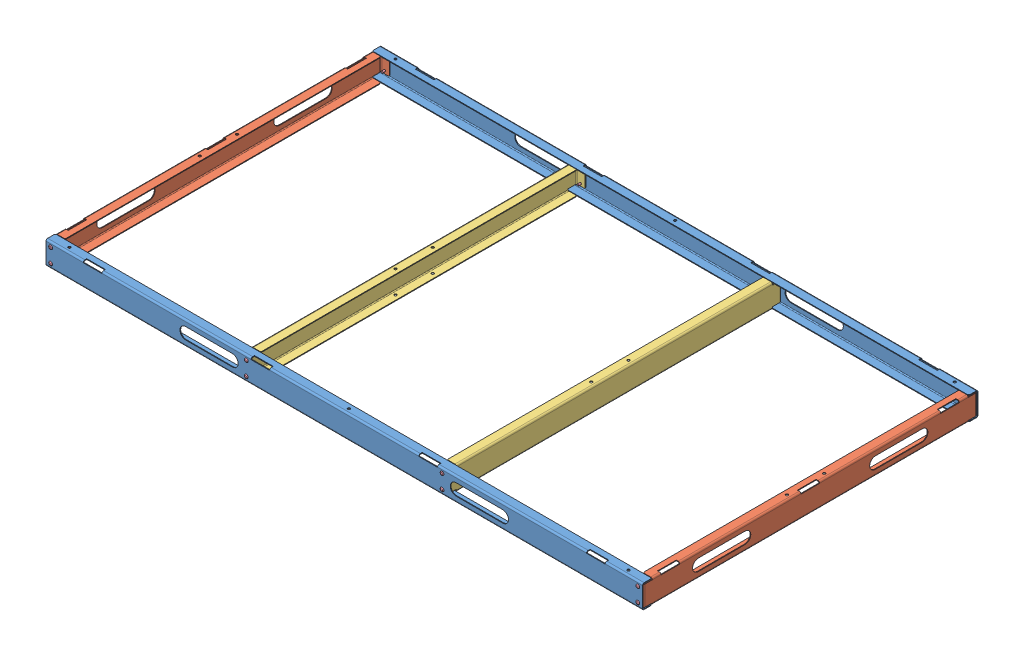
SolidWorks assembly GE-19063, configuration Default. Lengths in mm.
Overall size (1625.6 63.5 917.59).
22 component instances, 4 part files, 46 mates.
Components (placement in the parent):
- GE-19066-2: GE-19066 [Default] at (812.8 0 -457.2) x (0 0 -1) z (1 0 0) size (25.4 63.5 1625.6)
- GE-19064-2: GE-19064 [Default] at (-812.8 0 -430.5376) x (-1 0 0) z (0 0 -1) size (25.4 63.5 910.59)
- GE-19064-3: GE-19064 [Default] at (812.8 0 430.5224) size (25.4 63.5 910.59)
- GE-19066-3: GE-19066 [Default] at (-812.8 0 457.1848) x (0 0 1) z (-1 0 0) size (25.4 63.5 1625.6)
- GE-19065-1: GE-19065 [Default] at (279.4 0 -0.0076) size (25.4 63.5 910.59)
- GE-19065-2: GE-19065 [Default] at (-279.4 63.5 -0.0076) x (-1 0 0) z (0 0 1) size (25.4 63.5 910.59)
- rivet_.1875_.126-.25-2: rivet_.1875_.126-.25 [Default] at (-800.1 50.8 457.1848) size (10.01 10.01 13.03)
- rivet_.1875_.126-.25-10: rivet_.1875_.126-.25 [Default] at (-266.7 50.8 457.1848) x (0.959125 0.282984 0) z (0 0 1) size (10.01 10.01 13.03)
- rivet_.1875_.126-.25-11: rivet_.1875_.126-.25 [Default] at (-266.7 12.7 457.1848) x (0.928571 0.371154 0) z (0 0 1) size (10.01 10.01 13.03)
- rivet_.1875_.126-.25-12: rivet_.1875_.126-.25 [Default] at (266.7 50.8 457.1848) x (0.906989 0.421154 0) z (0 0 1) size (10.01 10.01 13.03)
- rivet_.1875_.126-.25-13: rivet_.1875_.126-.25 [Default] at (266.7 12.7 457.1848) x (0.902849 0.429957 0) z (0 0 1) size (10.01 10.01 13.03)
- rivet_.1875_.126-.25-14: rivet_.1875_.126-.25 [Default] at (800.1 50.8 457.1848) x (0.919615 0.39282 0) z (0 0 1) size (10.01 10.01 13.03)
- rivet_.1875_.126-.25-15: rivet_.1875_.126-.25 [Default] at (800.1 12.7 457.1848) x (0.952324 0.305088 0) z (0 0 1) size (10.01 10.01 13.03)
- rivet_.1875_.126-.25-18: rivet_.1875_.126-.25 [Default] at (-800.1 12.7 457.1848) x (0.987351 0.158553 0) z (0 0 1) size (10.01 10.01 13.03)
- rivet_.1875_.126-.25-20: rivet_.1875_.126-.25 [Default] at (800.1 50.8 -457.2) x (1 0 0) z (0 0 -1) size (10.01 10.01 13.03)
- rivet_.1875_.126-.25-21: rivet_.1875_.126-.25 [Default] at (800.1 12.7 -457.2) x (0.987351 0.158553 0) z (0 0 -1) size (10.01 10.01 13.03)
- rivet_.1875_.126-.25-22: rivet_.1875_.126-.25 [Default] at (266.7 50.8 -457.2) x (0.959125 0.282984 0) z (0 0 -1) size (10.01 10.01 13.03)
- rivet_.1875_.126-.25-23: rivet_.1875_.126-.25 [Default] at (266.7 12.7 -457.2) x (0.928571 0.371154 0) z (0 0 -1) size (10.01 10.01 13.03)
- rivet_.1875_.126-.25-24: rivet_.1875_.126-.25 [Default] at (-266.7 50.8 -457.2) x (0.906989 0.421154 0) z (0 0 -1) size (10.01 10.01 13.03)
- rivet_.1875_.126-.25-25: rivet_.1875_.126-.25 [Default] at (-266.7 12.7 -457.2) x (0.902849 0.429957 0) z (0 0 -1) size (10.01 10.01 13.03)
- rivet_.1875_.126-.25-26: rivet_.1875_.126-.25 [Default] at (-800.1 50.8 -457.2) x (0.919615 0.39282 0) z (0 0 -1) size (10.01 10.01 13.03)
- rivet_.1875_.126-.25-27: rivet_.1875_.126-.25 [Default] at (-800.1 12.7 -457.2) x (0.952324 0.305088 0) z (0 0 -1) size (10.01 10.01 13.03)
Mates (geometry in assembly coordinates):
- Distance5: distance = 457.2 mm: plane of GE-19066-2 through (812.8 0 -457.2) normal (0 0 -1); plane of assembly through (0 0 0) normal (0 0 1)
- Coincident19: coincident: plane of GE-19066-2 through (0 0 -457.2) normal (1 0 0); plane of assembly through (0 0 0) normal (1 0 0)
- Coincident20: coincident: plane of GE-19066-2 through (812.8 0 -457.2) normal (0 -1 0); plane of assembly through (0 0 0) normal (0 1 0)
- Concentric1: concentric: cylinder of GE-19066-2 through (-800.1 50.8 -431.8) axis (0 0 -1) radius 2.4638; cylinder of GE-19064-2 through (-800.1 50.8 455.2874) axis (0 0 -1) radius 2.4638
- Coincident21: coincident: plane of GE-19066-2 through (812.8 0 -455.3026) normal (0 0 1); plane of GE-19064-2 through (-812.8 0 -455.3026) normal (0 0 -1)
- Concentric4: concentric: cylinder of GE-19066-2 through (800.1 50.8 -431.8) axis (0 0 -1) radius 2.4638; cylinder of GE-19064-3 through (800.1 50.8 -455.3026) axis (0 0 1) radius 2.4638
- Coincident24: coincident: plane of GE-19066-2 through (812.8 0 -455.3026) normal (0 0 1); plane of GE-19064-3 through (812.8 0 -455.3026) normal (0 0 -1)
- Concentric5: concentric: cylinder of assembly; cylinder of assembly; cylinder of GE-19064-2 through (-800.1 50.8 455.2874) axis (0 0 -1) radius 2.4638; cylinder of GE-19066-3 through (-800.1 50.8 431.7848) axis (0 0 1) radius 2.4638
- Coincident25: coincident: plane of assembly; plane of assembly; plane of GE-19064-2 through (-812.8 0 455.2874) normal (0 0 1); plane of GE-19066-3 through (-812.8 0 455.2874) normal (0 0 -1)
- Concentric6: concentric: cylinder of assembly; cylinder of assembly; cylinder of GE-19066-3 through (266.7 50.8 431.7848) axis (0 0 1) radius 2.4638; cylinder of GE-19065-1 through (266.7 50.8 -455.3026) axis (0 0 1) radius 2.4638
- Coincident26: coincident: plane of assembly; plane of assembly; plane of GE-19066-3 through (-812.8 0 455.2874) normal (0 0 -1); plane of GE-19065-1 through (279.4 0 455.2874) normal (0 0 1)
- Concentric8: concentric: cylinder of assembly; cylinder of assembly; cylinder of GE-19066-3 through (-266.7 12.7 431.7848) axis (0 0 1) radius 2.4638; cylinder of GE-19065-2 through (-266.7 12.7 -455.3026) axis (0 0 1) radius 2.4638
- Concentric9: concentric: cylinder of assembly; cylinder of assembly; cylinder of GE-19066-3 through (-266.7 50.8 431.7848) axis (0 0 1) radius 2.4638; cylinder of GE-19065-2 through (-266.7 50.8 -455.3026) axis (0 0 1) radius 2.4638
- Coincident28: coincident: plane of assembly; plane of assembly; plane of GE-19066-3 through (-812.8 0 455.2874) normal (0 0 -1); plane of GE-19065-2 through (-279.4 63.5 455.2874) normal (0 0 1)
- Concentric10: concentric: cylinder of assembly; cylinder of assembly; cylinder of GE-19066-3 through (-800.1 50.8 431.7848) axis (0 0 1) radius 2.4638; cylinder of rivet_.1875_.126-.25-2 through (-800.1 50.8 445.7548) axis (0 0 1) radius 2.3813
- Coincident29: coincident: plane of assembly; plane of assembly; plane of GE-19066-3 through (-812.8 0 457.1848) normal (0 0 1); plane of rivet_.1875_.126-.25-2 through (-800.1 50.8 457.1848) normal (0 0 -1)
- Coincident32: coincident: plane of assembly; plane of assembly; plane of GE-19066-3 through (-812.8 0 457.1848) normal (0 0 1); plane of rivet_.1875_.126-.25-10 through (-266.7 50.8 457.1848) normal (0 0 -1)
- Concentric14: concentric: cylinder of assembly; cylinder of assembly; cylinder of GE-19066-3 through (-266.7 50.8 431.7848) axis (0 0 1) radius 2.4638; cylinder of rivet_.1875_.126-.25-10 through (-266.7 50.8 445.7548) axis (0 0 1) radius 2.3813
- Coincident33: coincident: plane of assembly; plane of assembly; plane of GE-19066-3 through (-812.8 0 457.1848) normal (0 0 1); plane of rivet_.1875_.126-.25-11 through (-266.7 12.7 457.1848) normal (0 0 -1)
- Concentric15: concentric: cylinder of assembly; cylinder of assembly; cylinder of GE-19066-3 through (-266.7 12.7 431.7848) axis (0 0 1) radius 2.4638; cylinder of rivet_.1875_.126-.25-11 through (-266.7 12.7 445.7548) axis (0 0 1) radius 2.3813
- Coincident34: coincident: plane of assembly; plane of assembly; plane of GE-19066-3 through (-812.8 0 457.1848) normal (0 0 1); plane of rivet_.1875_.126-.25-12 through (266.7 50.8 457.1848) normal (0 0 -1)
- Concentric16: concentric: cylinder of assembly; cylinder of assembly; cylinder of GE-19066-3 through (266.7 50.8 431.7848) axis (0 0 1) radius 2.4638; cylinder of rivet_.1875_.126-.25-12 through (266.7 50.8 445.7548) axis (0 0 1) radius 2.3813
- Coincident35: coincident: plane of assembly; plane of assembly; plane of GE-19066-3 through (-812.8 0 457.1848) normal (0 0 1); plane of rivet_.1875_.126-.25-13 through (266.7 12.7 457.1848) normal (0 0 -1)
- Concentric17: concentric: cylinder of assembly; cylinder of assembly; cylinder of GE-19066-3 through (266.7 12.7 431.7848) axis (0 0 1) radius 2.4638; cylinder of rivet_.1875_.126-.25-13 through (266.7 12.7 445.7548) axis (0 0 1) radius 2.3813
- Coincident36: coincident: plane of assembly; plane of assembly; plane of GE-19066-3 through (-812.8 0 457.1848) normal (0 0 1); plane of rivet_.1875_.126-.25-14 through (800.1 50.8 457.1848) normal (0 0 -1)
- Concentric18: concentric: cylinder of assembly; cylinder of assembly; cylinder of GE-19066-3 through (800.1 50.8 431.7848) axis (0 0 1) radius 2.4638; cylinder of rivet_.1875_.126-.25-14 through (800.1 50.8 445.7548) axis (0 0 1) radius 2.3813
- Coincident37: coincident: plane of assembly; plane of assembly; plane of GE-19066-3 through (-812.8 0 457.1848) normal (0 0 1); plane of rivet_.1875_.126-.25-15 through (800.1 12.7 457.1848) normal (0 0 -1)
- Concentric19: concentric: cylinder of assembly; cylinder of assembly; cylinder of GE-19066-3 through (800.1 12.7 431.7848) axis (0 0 1) radius 2.4638; cylinder of rivet_.1875_.126-.25-15 through (800.1 12.7 445.7548) axis (0 0 1) radius 2.3813
- Concentric20: concentric: cylinder of assembly; cylinder of assembly; cylinder of GE-19066-3 through (-800.1 12.7 431.7848) axis (0 0 1) radius 2.4638; cylinder of rivet_.1875_.126-.25-18 through (-800.1 12.7 445.7548) axis (0 0 1) radius 2.3813
- Coincident39: coincident: plane of assembly; plane of assembly; plane of GE-19066-3 through (-812.8 0 457.1848) normal (0 0 1); plane of rivet_.1875_.126-.25-18 through (-800.1 12.7 457.1848) normal (0 0 -1)
- Concentric21: concentric: cylinder of GE-19066-2 through (800.1 50.8 -431.8) axis (0 0 -1) radius 2.4638; cylinder of rivet_.1875_.126-.25-20 through (800.1 50.8 -445.77) axis (0 0 -1) radius 2.3813
- Coincident40: coincident: plane of GE-19066-2 through (812.8 0 -457.2) normal (0 0 -1); plane of rivet_.1875_.126-.25-20 through (800.1 50.8 -457.2) normal (0 0 1)
- Concentric22: concentric: cylinder of GE-19066-2 through (800.1 12.7 -431.8) axis (0 0 -1) radius 2.4638; cylinder of rivet_.1875_.126-.25-21 through (800.1 12.7 -445.77) axis (0 0 -1) radius 2.3813
- Coincident42: coincident: plane of GE-19066-2 through (812.8 0 -457.2) normal (0 0 -1); plane of rivet_.1875_.126-.25-21 through (800.1 12.7 -457.2) normal (0 0 1)
- Coincident43: coincident: plane of GE-19066-2 through (812.8 0 -457.2) normal (0 0 -1); plane of rivet_.1875_.126-.25-22 through (266.7 50.8 -457.2) normal (0 0 1)
- Concentric23: concentric: cylinder of GE-19066-2 through (266.7 50.8 -431.8) axis (0 0 -1) radius 2.4638; cylinder of rivet_.1875_.126-.25-22 through (266.7 50.8 -445.77) axis (0 0 -1) radius 2.3813
- Coincident44: coincident: plane of GE-19066-2 through (812.8 0 -457.2) normal (0 0 -1); plane of rivet_.1875_.126-.25-23 through (266.7 12.7 -457.2) normal (0 0 1)
- Concentric24: concentric: cylinder of GE-19066-2 through (266.7 12.7 -431.8) axis (0 0 -1) radius 2.4638; cylinder of rivet_.1875_.126-.25-23 through (266.7 12.7 -445.77) axis (0 0 -1) radius 2.3813
- Coincident45: coincident: plane of GE-19066-2 through (812.8 0 -457.2) normal (0 0 -1); plane of rivet_.1875_.126-.25-24 through (-266.7 50.8 -457.2) normal (0 0 1)
- Concentric25: concentric: cylinder of GE-19066-2 through (-266.7 50.8 -431.8) axis (0 0 -1) radius 2.4638; cylinder of rivet_.1875_.126-.25-24 through (-266.7 50.8 -445.77) axis (0 0 -1) radius 2.3813
- Coincident46: coincident: plane of GE-19066-2 through (812.8 0 -457.2) normal (0 0 -1); plane of rivet_.1875_.126-.25-25 through (-266.7 12.7 -457.2) normal (0 0 1)
- Concentric26: concentric: cylinder of GE-19066-2 through (-266.7 12.7 -431.8) axis (0 0 -1) radius 2.4638; cylinder of rivet_.1875_.126-.25-25 through (-266.7 12.7 -445.77) axis (0 0 -1) radius 2.3813
- Coincident47: coincident: plane of GE-19066-2 through (812.8 0 -457.2) normal (0 0 -1); plane of rivet_.1875_.126-.25-26 through (-800.1 50.8 -457.2) normal (0 0 1)
- Concentric27: concentric: cylinder of GE-19066-2 through (-800.1 50.8 -431.8) axis (0 0 -1) radius 2.4638; cylinder of rivet_.1875_.126-.25-26 through (-800.1 50.8 -445.77) axis (0 0 -1) radius 2.3813
- Coincident48: coincident: plane of GE-19066-2 through (812.8 0 -457.2) normal (0 0 -1); plane of rivet_.1875_.126-.25-27 through (-800.1 12.7 -457.2) normal (0 0 1)
- Concentric28: concentric: cylinder of GE-19066-2 through (-800.1 12.7 -431.8) axis (0 0 -1) radius 2.4638; cylinder of rivet_.1875_.126-.25-27 through (-800.1 12.7 -445.77) axis (0 0 -1) radius 2.3813
